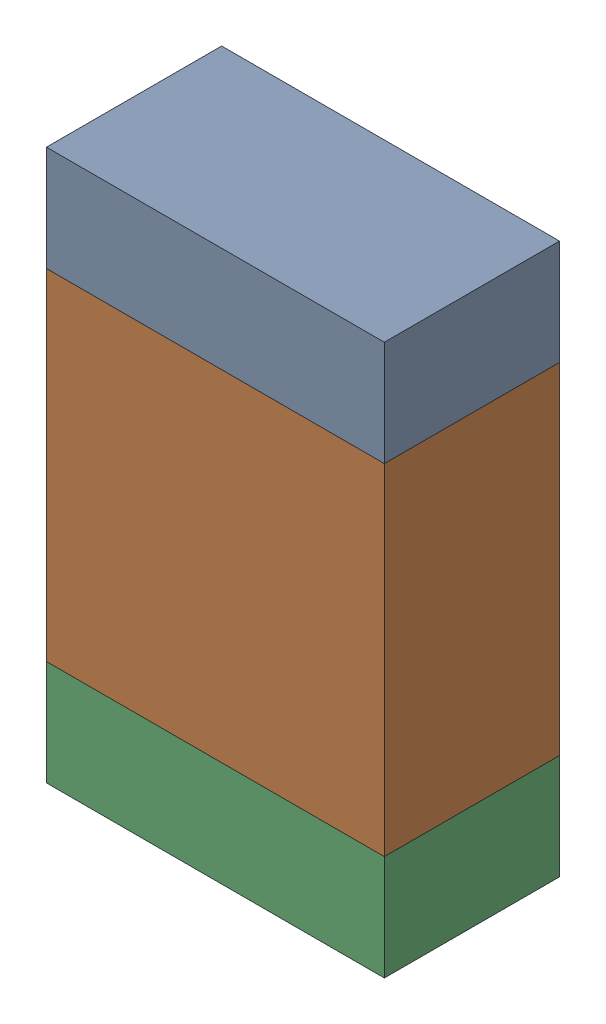
SolidWorks assembly R11-2, configuration Default. Lengths in mm.
Overall size (1.35 2.2 0.7).
6 component instances, 2 part files, 0 mates.
Components (placement in the parent):
- 959207304-2-1: 959207304-2 [Default] at (133.9849 94.0691 0) size (1.35 0.42 0.7)
  - Extruded-70-1: Extruded-70 [Default] at origin size (1.35 0.42 0.7)
- 959207440-2-1: 959207440-2 [Default] at (133.9849 93.1791 0) size (1.35 1.36 0.7)
  - Extruded-71-1: Extruded-71 [Default] at origin size (1.35 1.36 0.7)
- 959207304-2-2: 959207304-2 [Default] at (133.9849 92.2891 0) size (1.35 0.42 0.7)
  - Extruded-70-1: Extruded-70 [Default] at origin size (1.35 0.42 0.7)
